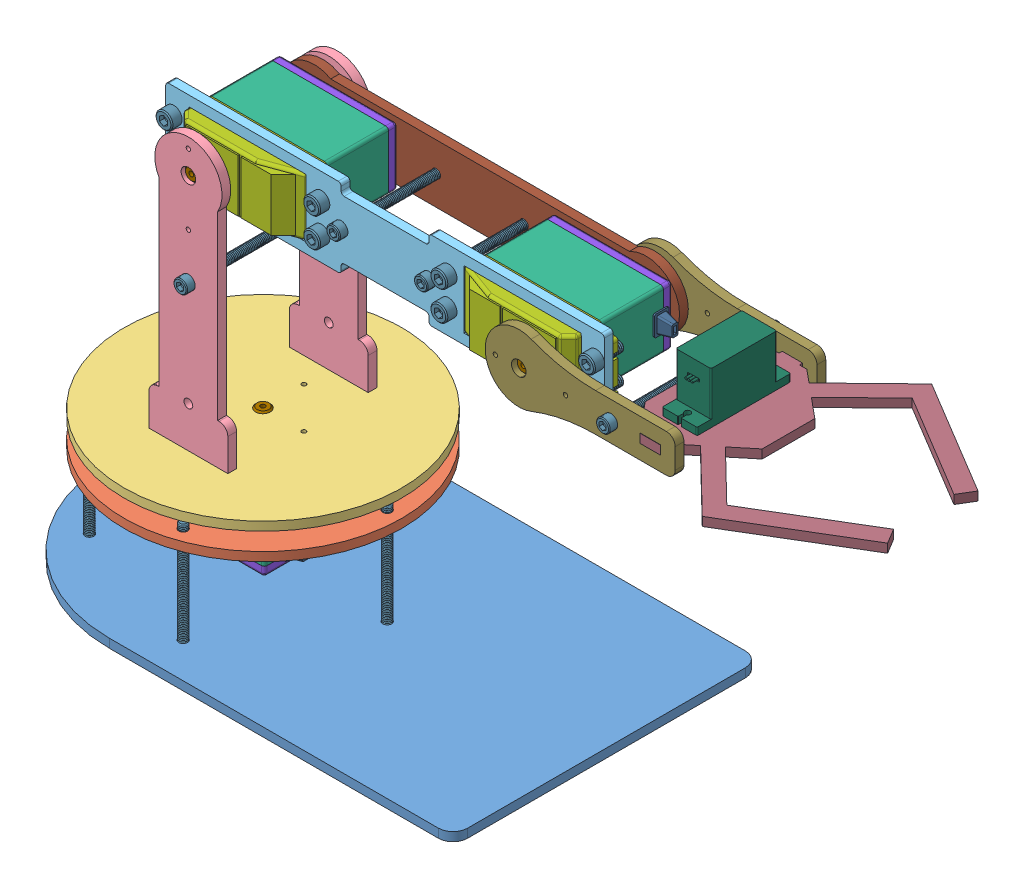
SolidWorks assembly robot_esamble_1_v0, configuration Predeterminado. Lengths in mm.
Overall size (282.35 148.29 105).
56 component instances, 17 part files, 91 mates.
Components (placement in the parent):
- A_pieza_arm_robot_v0-1: A_pieza_arm_robot_v0 [Predeterminado] x (0 0 -1) z (0 1 0) size (105 170 3)
- B_pieza_arm_robot_v0-1: B_pieza_arm_robot_v0 [Predeterminado] at (0 33 0) x (-1 0 0) z (0 1 0) size (95 95 3)
- H_pieza_arm_robot_v0-1: H_pieza_arm_robot_v0 [Predeterminado] at (0 42 0) x (0 0 -1) z (0 1 0) size (95 95 3)
- D_pieza_arm_robot_v0-1: D_pieza_arm_robot_v0 [piexa_motor_leva] at (0 126.5 25.5) x (-1 0 0) z (0 0 -1) size (27 96 3)
- D_pieza_arm_robot_v0-2: D_pieza_arm_robot_v0 [Predeterminado] at (0 126.5 -22.5) x (-1 0 0) z (0 0 -1) size (27 96 3)
- C_pieza_arm_robot_v0-1: C_pieza_arm_robot_v0 [Predeterminado] at (56.75 126.5 12) x (-1 0 0) z (0 0 1) size (150 27 3)
- Servomoteur Futuba S3003-2: Servomoteur Futuba S3003 [Défaut] at (104.1357 166.9 3.2642) x (1 0 0) z (0 -1 0) size (55.5 42.98 32.41)
  - Boitier-1: Boitier [Défaut] at (8.3252 -16.2642 40.4) size (40.4 21 20)
  - Couvercle supérieure-1: Couvercle supérieure [Défaut] at (9.3643 6.7358 40.4) size (55.5 13 20)
  - Couvercle inférieure-1: Couvercle inférieure [Défaut] at (4.9957 -19.3642 40.4) size (40.4 3.1 20)
  - Axe-1: Axe [Défaut] at (9.3643 15.2358 40.4) size (5 16 5)
  - Passe fil-1: Passe fil [Défaut] at (17.8143 -15.2642 40.4) x (0 0 -1) z (1 0 0) size (7 5 7.5)
  - Palonnier-1: Palonnier [Défaut] at (9.3643 21.7358 40.4) x (0.465117 0 -0.885249) z (0 1 0) size (24 24 5) (hidden)
  - Vis CBL Z, M 2.5 - 5-1: Vis CBL Z, M 2.5 - 5 [Défaut] at (9.3643 21.7358 40.4) x (0.991239 0 0.132079) z (0 1 0) size (5 5 6.88) (hidden)
- Servomoteur Futuba S3003-3: Servomoteur Futuba S3003 [Défaut] at (9.3643 86.1 3.2642) x (-1 0 0) z (0 1 0) size (55.5 42.98 32.41)
  - Boitier-1: Boitier [Défaut] at (8.3252 -16.2642 40.4) size (40.4 21 20)
  - Couvercle supérieure-1: Couvercle supérieure [Défaut] at (9.3643 6.7358 40.4) size (55.5 13 20)
  - Couvercle inférieure-1: Couvercle inférieure [Défaut] at (4.9957 -19.3642 40.4) size (40.4 3.1 20)
  - Axe-1: Axe [Défaut] at (9.3643 15.2358 40.4) size (5 16 5)
  - Passe fil-1: Passe fil [Défaut] at (17.8143 -15.2642 40.4) x (0 0 -1) z (1 0 0) size (7 5 7.5)
  - Palonnier-1: Palonnier [Défaut] at (9.3643 21.7358 40.4) x (0.465117 0 -0.885249) z (0 1 0) size (24 24 5) (hidden)
  - Vis CBL Z, M 2.5 - 5-1: Vis CBL Z, M 2.5 - 5 [Défaut] at (9.3643 21.7358 40.4) x (0.991239 0 0.132079) z (0 1 0) size (5 5 6.88) (hidden)
- E_pieza_arm_robot_v0-1: E_pieza_arm_robot_v0 [Predeterminado] at (56.75 126.5 -20.5) x (0 -1 0) z (0 0 1) size (23 136.5 3)
- F_pieza_arm_robot_v0-1: F_pieza_arm_robot_v0 [Predeterminado] at (113.5 126.5 26) x (0 -1 0) z (0 0 -1) size (23 65 3)
- F_pieza_arm_robot_v0-2: F_pieza_arm_robot_v0 [Predeterminado] at (113.5 126.5 -22.5) x (0 -1 0) z (0 0 -1) size (23 65 3)
- G_pieza_arm_robot_v0-1: G_pieza_arm_robot_v0 [Predeterminado] at (158.5 124.95 0.75) x (0 0 1) z (0 1 0) size (78.46 83.35 3)
- socket head cap screw_ai-1: socket head cap screw_ai [HX-SHCS 0.112-48x1.5x1.5-S] at (13.1332 -2.8448 -40.4199) x (0 1 0) z (0 0 1) size (40.94 4.65 4.65)
- socket head cap screw_ai-2: socket head cap screw_ai [HX-SHCS 0.112-48x1.5x1.5-S] at (-34.3832 -2.8448 -24.9809) x (0 1 0) z (0 0 1) size (40.94 4.65 4.65)
- socket head cap screw_ai-3: socket head cap screw_ai [HX-SHCS 0.112-48x1.5x1.5-S] at (-34.3832 -2.8448 24.9809) x (0 1 0) z (0 0 1) size (40.94 4.65 4.65)
- socket head cap screw_ai-4: socket head cap screw_ai [HX-SHCS 0.112-48x1.5x1.5-S] at (13.1332 -2.8448 40.4199) x (0 1 0) z (0 0 1) size (40.94 4.65 4.65)
- socket head cap screw_ai-5: socket head cap screw_ai [HX-SHCS 0.112-48x1.5x1.5-S] at (42.5 -2.8448 0) x (0 1 0) z (0 0 1) size (40.94 4.65 4.65)
- Servomoteur Futuba S3003-4: Servomoteur Futuba S3003 [Défaut] at (-9.3643 24.2642 -40.4) size (55.5 42.98 32.41)
  - Boitier-1: Boitier [Défaut] at (8.3252 -16.2642 40.4) size (40.4 21 20)
  - Couvercle supérieure-1: Couvercle supérieure [Défaut] at (9.3643 6.7358 40.4) size (55.5 13 20)
  - Couvercle inférieure-1: Couvercle inférieure [Défaut] at (4.9957 -19.3642 40.4) size (40.4 3.1 20)
  - Axe-1: Axe [Défaut] at (9.3643 15.2358 40.4) size (5 16 5)
  - Passe fil-1: Passe fil [Défaut] at (17.8143 -15.2642 40.4) x (0 0 -1) z (1 0 0) size (7 5 7.5)
  - Palonnier-1: Palonnier [Défaut] at (9.3643 21.7358 40.4) x (0.465117 0 -0.885249) z (0 1 0) size (24 24 5) (hidden)
  - Vis CBL Z, M 2.5 - 5-1: Vis CBL Z, M 2.5 - 5 [Défaut] at (9.3643 21.7358 40.4) x (0.991239 0 0.132079) z (0 1 0) size (5 5 6.88) (hidden)
- socket head cap screw_ai-6: socket head cap screw_ai [HX-SHCS 0.112-48x2.25x2.25-S] at (0 95 28.3448) x (0 0 -1) z (1 0 0) size (59.99 4.65 4.65)
- socket head cap screw_ai-11: socket head cap screw_ai [HX-SHCS 0.112-48x1.5x1.5-S] at (41.75 126.5 17.8448) x (0 0 -1) z (1 0 0) size (40.94 4.65 4.65)
- socket head cap screw_ai-12: socket head cap screw_ai [HX-SHCS 0.112-48x1.5x1.5-S] at (71.75 126.5 17.8448) x (0 0 -1) z (1 0 0) size (40.94 4.65 4.65)
- socket head cap screw_ai-13: socket head cap screw_ai [HX-SHCS 0.112-48x2.25x2.25-S] at (145 126.5 28.8448) x (0 0 -1) z (1 0 0) size (59.99 4.65 4.65)
- socket head cap screw_ai-14: socket head cap screw_ai [HX-SHCS 0.138-40x0.3125x0.3125-S] at (35 131.5 18.5052) x (0 0 -1) z (1 0 0) size (11.44 5.74 5.74)
- socket head cap screw_ai-15: socket head cap screw_ai [HX-SHCS 0.138-40x0.3125x0.3125-S] at (35 121.5 18.5052) x (0 0 -1) z (1 0 0) size (11.44 5.74 5.74)
- socket head cap screw_ai-16: socket head cap screw_ai [HX-SHCS 0.138-40x0.3125x0.3125-S] at (-15.5 131.5 18.5052) x (0 0 -1) z (1 0 0) size (11.44 5.74 5.74)
- socket head cap screw_ai-17: socket head cap screw_ai [HX-SHCS 0.138-40x0.3125x0.3125-S] at (-15.5 121.5 18.5052) x (0 0 -1) z (1 0 0) size (11.44 5.74 5.74)
- socket head cap screw_ai-18: socket head cap screw_ai [HX-SHCS 0.138-40x0.3125x0.3125-S] at (78.5 131.5 18.5052) x (0 0 -1) z (1 0 0) size (11.44 5.74 5.74)
- socket head cap screw_ai-19: socket head cap screw_ai [HX-SHCS 0.138-40x0.3125x0.3125-S] at (78.5 121.5 18.5052) x (0 0 -1) z (1 0 0) size (11.44 5.74 5.74)
- socket head cap screw_ai-20: socket head cap screw_ai [HX-SHCS 0.138-40x0.3125x0.3125-S] at (129 131.5 18.5052) x (0 0 -1) z (1 0 0) size (11.44 5.74 5.74)
- socket head cap screw_ai-21: socket head cap screw_ai [HX-SHCS 0.138-40x0.3125x0.3125-S] at (129 121.5 18.5052) x (0 0 -1) z (1 0 0) size (11.44 5.74 5.74)
- socket head cap screw_ai-22: socket head cap screw_ai [HX-SHCS 0.138-40x0.3125x0.3125-S] at (15.5 39.5052 5) x (0 -1 0) z (0 0 1) size (11.44 5.74 5.74)
- socket head cap screw_ai-23: socket head cap screw_ai [HX-SHCS 0.138-40x0.3125x0.3125-S] at (15.5 39.5052 -5) x (0 -1 0) z (0 0 1) size (11.44 5.74 5.74)
- socket head cap screw_ai-24: socket head cap screw_ai [HX-SHCS 0.138-40x0.3125x0.3125-S] at (-35 39.5052 5) x (0 -1 0) z (0 0 1) size (11.44 5.74 5.74)
- socket head cap screw_ai-25: socket head cap screw_ai [HX-SHCS 0.138-40x0.3125x0.3125-S] at (-35 39.5052 -5) x (0 -1 0) z (0 0 1) size (11.44 5.74 5.74)
- Towerpro Micro Servo 9g-1: Towerpro Micro Servo 9g [Varsayılan] at (159.5 145.45 1) x (1 0 0) z (0 0 -1) size (12 30 32)
Mates (geometry in assembly coordinates):
- Coincidente1: coincident anti-aligned: plane of A_pieza_arm_robot_v0-1 through (0 0 0) normal (0 -1 0)
- Coincidente2: coincident anti-aligned: plane of A_pieza_arm_robot_v0-1 through (0 0 0) normal (0 0 -1)
- Coincidente3: coincident anti-aligned: plane of A_pieza_arm_robot_v0-1 through (0 0 0) normal (-1 0 0)
- Distancia1: distance = 30 mm anti-aligned: plane of B_pieza_arm_robot_v0-1 through (0 33 0) normal (0 -1 0); plane of A_pieza_arm_robot_v0-1 through (0 3 0) normal (0 1 0)
- Concéntrica1: concentric aligned: cylinder of A_pieza_arm_robot_v0-1 through (42.5 0 0) axis (0 1 0) radius 1.5; cylinder of B_pieza_arm_robot_v0-1 through (42.5 33 0) axis (0 1 0) radius 1.5
- Concéntrica2: concentric aligned: cylinder of A_pieza_arm_robot_v0-1 through (-34.3832 0 24.9809) axis (0 1 0) radius 1.5; cylinder of B_pieza_arm_robot_v0-1 through (-34.3832 33 24.9809) axis (0 1 0) radius 1.5
- Concéntrica3: concentric aligned: cylinder of B_pieza_arm_robot_v0-1 through (0 36 0) axis (0 -1 0) radius 47.5; cylinder of H_pieza_arm_robot_v0-1 through (0 45 0) axis (0 -1 0) radius 47.5
- Distancia2: distance = 6 mm anti-aligned: plane of B_pieza_arm_robot_v0-1 through (0 36 0) normal (0 1 0); plane of H_pieza_arm_robot_v0-1 through (0 42 0) normal (0 -1 0)
- Coincidente6: coincident anti-aligned: plane of H_pieza_arm_robot_v0-1 through (2.5 42 25.5) normal (0 0 -1); plane of D_pieza_arm_robot_v0-1 through (0 126.5 25.5) normal (0 0 1)
- Coincidente7: coincident anti-aligned: plane of H_pieza_arm_robot_v0-1 through (10.5 42 22.5) normal (-1 0 0); plane of D_pieza_arm_robot_v0-1 through (10.5 45 25.5) normal (1 0 0)
- Coincidente8: coincident anti-aligned: plane of H_pieza_arm_robot_v0-1 through (0 45 0) normal (0 1 0); plane of D_pieza_arm_robot_v0-1 through (0 45 22.5) normal (0 -1 0)
- Coincidente9: coincident anti-aligned: plane of H_pieza_arm_robot_v0-1 through (-10.5 42 -22.5) normal (1 0 0); plane of D_pieza_arm_robot_v0-2 through (-10.5 45 -22.5) normal (-1 0 0)
- Coincidente10: coincident anti-aligned: plane of H_pieza_arm_robot_v0-1 through (-10.5 42 -25.5) normal (0 0 1); plane of D_pieza_arm_robot_v0-2 through (0 126.5 -25.5) normal (0 0 -1)
- Coincidente12: coincident anti-aligned: plane of H_pieza_arm_robot_v0-1 through (0 45 0) normal (0 1 0); plane of D_pieza_arm_robot_v0-2 through (0 45 -25.5) normal (0 -1 0)
- Coincidente13: coincident anti-aligned: plane of C_pieza_arm_robot_v0-1 through (56.75 126.5 12) normal (0 0 -1); plane of Servomoteur Futuba S3003-2/Couvercle supérieure-1 through (78.5 131.5 12) normal (0 0 1)
- Concéntrica6: concentric anti-aligned: cylinder of C_pieza_arm_robot_v0-1 through (129 121.5 12) axis (0 0 1) radius 2; cylinder of Servomoteur Futuba S3003-2/Couvercle supérieure-1 through (129 121.5 12) axis (0 0 -1) radius 2
- Concéntrica7: concentric anti-aligned: cylinder of C_pieza_arm_robot_v0-1 through (129 131.5 12) axis (0 0 1) radius 2; cylinder of Servomoteur Futuba S3003-2/Couvercle supérieure-1 through (129 131.5 12) axis (0 0 -1) radius 2
- Coincidente14: coincident anti-aligned: plane of C_pieza_arm_robot_v0-1 through (56.75 126.5 12) normal (0 0 -1); plane of Servomoteur Futuba S3003-3/Couvercle supérieure-1 through (35 121.5 12) normal (0 0 1)
- Concéntrica8: concentric anti-aligned: cylinder of C_pieza_arm_robot_v0-1 through (-15.5 121.5 12) axis (0 0 1) radius 2; cylinder of Servomoteur Futuba S3003-3/Couvercle supérieure-1 through (-15.5 121.5 12) axis (0 0 -1) radius 2
- Concéntrica9: concentric anti-aligned: cylinder of C_pieza_arm_robot_v0-1 through (-15.5 131.5 12) axis (0 0 1) radius 2; cylinder of Servomoteur Futuba S3003-3/Couvercle supérieure-1 through (-15.5 131.5 12) axis (0 0 -1) radius 2
- Concéntrica10: concentric anti-aligned: cylinder of D_pieza_arm_robot_v0-1 through (0 126.5 25.5) axis (0 0 -1) radius 2.5; cylinder of Servomoteur Futuba S3003-3/Axe-1 through (0 126.5 8.5) axis (0 0 1) radius 2.5
- Distancia3: distance = 1 mm aligned: plane of D_pieza_arm_robot_v0-1 through (0 126.5 25.5) normal (0 0 1); plane of Servomoteur Futuba S3003-3/Axe-1 through (0 126.5 24.5) normal (0 0 1)
- Concéntrica11: concentric anti-aligned: cylinder of D_pieza_arm_robot_v0-2 through (0 126.5 -22.5) axis (0 0 -1) radius 2.5; cylinder of E_pieza_arm_robot_v0-1 through (0 126.5 -20.5) axis (0 0 1) radius 1.5
- Distancia4: distance = 2 mm anti-aligned: plane of E_pieza_arm_robot_v0-1 through (56.75 126.5 -20.5) normal (0 0 -1); plane of D_pieza_arm_robot_v0-2 through (0 126.5 -22.5) normal (0 0 1)
- Paralelo3: parallel aligned: plane of C_pieza_arm_robot_v0-1 through (41.75 116.5 15) normal (0 -1 0); plane of E_pieza_arm_robot_v0-1 through (56.75 116.5 -17.5) normal (0 -1 0)
- Concéntrica16: concentric anti-aligned: cylinder of Servomoteur Futuba S3003-2/Axe-1 through (113.5 126.5 8.5) axis (0 0 1) radius 2.5; cylinder of F_pieza_arm_robot_v0-1 through (113.5 126.5 26) axis (0 0 -1) radius 2.5
- Distancia6: distance = 8 mm anti-aligned: plane of F_pieza_arm_robot_v0-1 through (113.5 126.5 23) normal (0 0 -1); plane of C_pieza_arm_robot_v0-1 through (56.75 126.5 15) normal (0 0 1)
- Concéntrica17: concentric anti-aligned: cylinder of E_pieza_arm_robot_v0-1 through (113.5 126.5 -20.5) axis (0 0 1) radius 1.5; cylinder of F_pieza_arm_robot_v0-2 through (113.5 126.5 -22.5) axis (0 0 -1) radius 2.5
- Distancia7: distance = 2 mm anti-aligned: plane of F_pieza_arm_robot_v0-2 through (113.5 126.5 -22.5) normal (0 0 1); plane of E_pieza_arm_robot_v0-1 through (56.75 126.5 -20.5) normal (0 0 -1)
- Coincidente21: coincident anti-aligned: plane of F_pieza_arm_robot_v0-1 through (155 124.95 26) normal (0 1 0); plane of G_pieza_arm_robot_v0-1 through (158.5 124.95 0.75) normal (0 -1 0)
- Coincidente23: coincident aligned: plane of F_pieza_arm_robot_v0-1 through (113.5 126.5 26) normal (0 0 1); plane of G_pieza_arm_robot_v0-1 through (158.5 127.95 26) normal (0 0 1)
- Coincidente24: coincident anti-aligned: plane of F_pieza_arm_robot_v0-1 through (162 124.95 26) normal (-1 0 0); plane of G_pieza_arm_robot_v0-1 through (162 127.95 0.75) normal (1 0 0)
- Coincidente25: coincident anti-aligned: plane of F_pieza_arm_robot_v0-2 through (155 124.95 -22.5) normal (0 1 0); plane of G_pieza_arm_robot_v0-1 through (158.5 124.95 0.75) normal (0 -1 0)
- Concéntrica21: concentric anti-aligned: cylinder of A_pieza_arm_robot_v0-1 through (13.1332 0 -40.4199) axis (0 1 0) radius 1.5; cylinder of socket head cap screw_ai-1 through (13.1332 -34.5948 -40.4199) axis (0 -1 0) radius 2.3241
- Coincidente29: coincident anti-aligned: plane of A_pieza_arm_robot_v0-1 through (0 0 0) normal (0 -1 0); plane of socket head cap screw_ai-1 through (10.8091 0 -40.4199) normal (0 1 0)
- Concéntrica22: concentric anti-aligned: cylinder of A_pieza_arm_robot_v0-1 through (-34.3832 0 -24.9809) axis (0 1 0) radius 1.5; cylinder of socket head cap screw_ai-2 through (-34.3832 -34.5948 -24.9809) axis (0 -1 0) radius 2.3241
- Coincidente30: coincident anti-aligned: plane of A_pieza_arm_robot_v0-1 through (0 0 0) normal (0 -1 0); plane of socket head cap screw_ai-2 through (-36.7073 0 -24.9809) normal (0 1 0)
- Concéntrica23: concentric anti-aligned: cylinder of A_pieza_arm_robot_v0-1 through (-34.3832 0 24.9809) axis (0 1 0) radius 1.5; cylinder of socket head cap screw_ai-3 through (-34.3832 -34.5948 24.9809) axis (0 -1 0) radius 2.3241
- Coincidente31: coincident anti-aligned: plane of A_pieza_arm_robot_v0-1 through (0 0 0) normal (0 -1 0); plane of socket head cap screw_ai-3 through (-36.7073 0 24.9809) normal (0 1 0)
- Concéntrica24: concentric anti-aligned: cylinder of A_pieza_arm_robot_v0-1 through (13.1332 0 40.4199) axis (0 1 0) radius 1.5; cylinder of socket head cap screw_ai-4 through (13.1332 -34.5948 40.4199) axis (0 -1 0) radius 2.3241
- Coincidente32: coincident anti-aligned: plane of A_pieza_arm_robot_v0-1 through (0 0 0) normal (0 -1 0); plane of socket head cap screw_ai-4 through (10.8091 0 40.4199) normal (0 1 0)
- Concéntrica25: concentric anti-aligned: cylinder of A_pieza_arm_robot_v0-1 through (42.5 0 0) axis (0 1 0) radius 1.5; cylinder of socket head cap screw_ai-5 through (42.5 -34.5948 0) axis (0 -1 0) radius 2.3241
- Coincidente33: coincident anti-aligned: plane of A_pieza_arm_robot_v0-1 through (0 0 0) normal (0 -1 0); plane of socket head cap screw_ai-5 through (40.1759 0 0) normal (0 1 0)
- Coincidente34: coincident anti-aligned: plane of B_pieza_arm_robot_v0-1 through (0 33 0) normal (0 -1 0); plane of Servomoteur Futuba S3003-4/Couvercle supérieure-1 through (-35 33 -5) normal (0 1 0)
- Concéntrica28: concentric anti-aligned: cylinder of B_pieza_arm_robot_v0-1 through (-35 33 5) axis (0 1 0) radius 2; cylinder of Servomoteur Futuba S3003-4/Couvercle supérieure-1 through (-35 33 5) axis (0 -1 0) radius 2
- Concéntrica29: concentric anti-aligned: cylinder of B_pieza_arm_robot_v0-1 through (-35 33 -5) axis (0 1 0) radius 2; cylinder of Servomoteur Futuba S3003-4/Couvercle supérieure-1 through (-35 33 -5) axis (0 -1 0) radius 2
- Concéntrica30: concentric anti-aligned: cylinder of D_pieza_arm_robot_v0-1 through (0 95 25.5) axis (0 0 -1) radius 1.5; cylinder of socket head cap screw_ai-6 through (0 95 60.0948) axis (0 0 1) radius 2.3241
- Coincidente35: coincident anti-aligned: plane of D_pieza_arm_robot_v0-1 through (0 126.5 25.5) normal (0 0 1); plane of socket head cap screw_ai-6 through (0 97.3241 25.5) normal (0 0 -1)
- Concéntrica31: concentric aligned: cylinder of C_pieza_arm_robot_v0-1 through (41.75 126.5 12) axis (0 0 1) radius 1.5; cylinder of socket head cap screw_ai-7 through (64.7787 129.0283 0.1988) axis (0.763622 0 0.645663) radius 2.3241
- Coincidente36: coincident anti-aligned: plane of C_pieza_arm_robot_v0-1 through (56.75 126.5 15) normal (0 0 1); plane of socket head cap screw_ai-7 through (38.3613 131.3524 -22.1378) normal (-0.763622 0 -0.645663)
- Concéntrica32: concentric aligned: cylinder of C_pieza_arm_robot_v0-1 through (71.75 126.5 12) axis (0 0 1) radius 1.5; cylinder of socket head cap screw_ai-9 through (84.113 130.8451 -22.6678) axis (0.763622 0 0.645663) radius 2.3241
- Coincidente38: coincident anti-aligned: plane of C_pieza_arm_robot_v0-1 through (56.75 126.5 15) normal (0 0 1); plane of socket head cap screw_ai-9 through (57.6956 133.1692 -45.0044) normal (-0.763622 0 -0.645663)
- Concéntrica33: concentric anti-aligned: cylinder of F_pieza_arm_robot_v0-1 through (145 126.5 26) axis (0 0 -1) radius 1.5; cylinder of socket head cap screw_ai-10 through (138.4716 144.3994 -69.9206) axis (0.763622 0 0.645663) radius 2.3241
- Coincidente39: coincident anti-aligned: plane of F_pieza_arm_robot_v0-1 through (113.5 126.5 26) normal (0 0 1); plane of socket head cap screw_ai-10 through (112.0542 146.7235 -92.2572) normal (-0.763622 0 -0.645663)
- Concéntrica34: concentric aligned: cylinder of C_pieza_arm_robot_v0-1 through (41.75 126.5 12) axis (0 0 1) radius 1.5; cylinder of socket head cap screw_ai-11 through (41.75 126.5 49.5948) axis (0 0 1) radius 2.3241
- Coincidente40: coincident anti-aligned: plane of C_pieza_arm_robot_v0-1 through (56.75 126.5 15) normal (0 0 1); plane of socket head cap screw_ai-11 through (41.75 128.8241 15) normal (0 0 -1)
- Concéntrica35: concentric aligned: cylinder of C_pieza_arm_robot_v0-1 through (71.75 126.5 12) axis (0 0 1) radius 1.5; cylinder of socket head cap screw_ai-12 through (71.75 126.5 49.5948) axis (0 0 1) radius 2.3241
- Coincidente41: coincident anti-aligned: plane of C_pieza_arm_robot_v0-1 through (56.75 126.5 15) normal (0 0 1); plane of socket head cap screw_ai-12 through (71.75 128.8241 15) normal (0 0 -1)
- Concéntrica36: concentric anti-aligned: cylinder of F_pieza_arm_robot_v0-1 through (145 126.5 26) axis (0 0 -1) radius 1.5; cylinder of socket head cap screw_ai-13 through (145 126.5 60.5948) axis (0 0 1) radius 2.3241
- Coincidente42: coincident anti-aligned: plane of F_pieza_arm_robot_v0-1 through (113.5 126.5 26) normal (0 0 1); plane of socket head cap screw_ai-13 through (145 128.8241 26) normal (0 0 -1)
- Concéntrica37: concentric aligned: cylinder of C_pieza_arm_robot_v0-1 through (35 131.5 12) axis (0 0 1) radius 2; cylinder of socket head cap screw_ai-14 through (35 131.5 50.2552) axis (0 0 1) radius 2.8702
- Coincidente43: coincident anti-aligned: plane of C_pieza_arm_robot_v0-1 through (56.75 126.5 15) normal (0 0 1); plane of socket head cap screw_ai-14 through (35 134.3702 15) normal (0 0 -1)
- Concéntrica38: concentric aligned: cylinder of C_pieza_arm_robot_v0-1 through (35 121.5 12) axis (0 0 1) radius 2; cylinder of socket head cap screw_ai-15 through (35 121.5 50.2552) axis (0 0 1) radius 2.8702
- Coincidente44: coincident anti-aligned: plane of C_pieza_arm_robot_v0-1 through (56.75 126.5 15) normal (0 0 1); plane of socket head cap screw_ai-15 through (35 124.3702 15) normal (0 0 -1)
- Concéntrica39: concentric aligned: cylinder of C_pieza_arm_robot_v0-1 through (-15.5 131.5 12) axis (0 0 1) radius 2; cylinder of socket head cap screw_ai-16 through (-15.5 131.5 50.2552) axis (0 0 1) radius 2.8702
- Coincidente45: coincident anti-aligned: plane of C_pieza_arm_robot_v0-1 through (56.75 126.5 15) normal (0 0 1); plane of socket head cap screw_ai-16 through (-15.5 134.3702 15) normal (0 0 -1)
- Concéntrica40: concentric aligned: cylinder of C_pieza_arm_robot_v0-1 through (-15.5 121.5 12) axis (0 0 1) radius 2; cylinder of socket head cap screw_ai-17 through (-15.5 121.5 50.2552) axis (0 0 1) radius 2.8702
- Coincidente46: coincident anti-aligned: plane of C_pieza_arm_robot_v0-1 through (56.75 126.5 15) normal (0 0 1); plane of socket head cap screw_ai-17 through (-15.5 124.3702 15) normal (0 0 -1)
- Concéntrica41: concentric aligned: cylinder of C_pieza_arm_robot_v0-1 through (78.5 131.5 12) axis (0 0 1) radius 2; cylinder of socket head cap screw_ai-18 through (78.5 131.5 50.2552) axis (0 0 1) radius 2.8702
- Coincidente47: coincident anti-aligned: plane of C_pieza_arm_robot_v0-1 through (56.75 126.5 15) normal (0 0 1); plane of socket head cap screw_ai-18 through (78.5 134.3702 15) normal (0 0 -1)
- Concéntrica42: concentric aligned: cylinder of C_pieza_arm_robot_v0-1 through (78.5 121.5 12) axis (0 0 1) radius 2; cylinder of socket head cap screw_ai-19 through (78.5 121.5 50.2552) axis (0 0 1) radius 2.8702
- Coincidente48: coincident anti-aligned: plane of C_pieza_arm_robot_v0-1 through (56.75 126.5 15) normal (0 0 1); plane of socket head cap screw_ai-19 through (78.5 124.3702 15) normal (0 0 -1)
- Concéntrica43: concentric aligned: cylinder of C_pieza_arm_robot_v0-1 through (129 131.5 12) axis (0 0 1) radius 2; cylinder of socket head cap screw_ai-20 through (129 131.5 50.2552) axis (0 0 1) radius 2.8702
- Coincidente49: coincident anti-aligned: plane of C_pieza_arm_robot_v0-1 through (56.75 126.5 15) normal (0 0 1); plane of socket head cap screw_ai-20 through (129 134.3702 15) normal (0 0 -1)
- Concéntrica44: concentric aligned: cylinder of C_pieza_arm_robot_v0-1 through (129 121.5 12) axis (0 0 1) radius 2; cylinder of socket head cap screw_ai-21 through (129 121.5 50.2552) axis (0 0 1) radius 2.8702
- Coincidente50: coincident anti-aligned: plane of C_pieza_arm_robot_v0-1 through (56.75 126.5 15) normal (0 0 1); plane of socket head cap screw_ai-21 through (129 124.3702 15) normal (0 0 -1)
- Concéntrica45: concentric aligned: cylinder of B_pieza_arm_robot_v0-1 through (15.5 33 5) axis (0 1 0) radius 2; cylinder of socket head cap screw_ai-22 through (15.5 71.2552 5) axis (0 1 0) radius 2.8702
- Coincidente51: coincident anti-aligned: plane of B_pieza_arm_robot_v0-1 through (0 36 0) normal (0 1 0); plane of socket head cap screw_ai-22 through (18.3702 36 5) normal (0 -1 0)
- Concéntrica46: concentric aligned: cylinder of B_pieza_arm_robot_v0-1 through (15.5 33 -5) axis (0 1 0) radius 2; cylinder of socket head cap screw_ai-23 through (15.5 71.2552 -5) axis (0 1 0) radius 2.8702
- Coincidente52: coincident anti-aligned: plane of B_pieza_arm_robot_v0-1 through (0 36 0) normal (0 1 0); plane of socket head cap screw_ai-23 through (18.3702 36 -5) normal (0 -1 0)
- Concéntrica47: concentric aligned: cylinder of B_pieza_arm_robot_v0-1 through (-35 33 5) axis (0 1 0) radius 2; cylinder of socket head cap screw_ai-24 through (-35 71.2552 5) axis (0 1 0) radius 2.8702
- Coincidente53: coincident anti-aligned: plane of B_pieza_arm_robot_v0-1 through (0 36 0) normal (0 1 0); plane of socket head cap screw_ai-24 through (-32.1298 36 5) normal (0 -1 0)
- Concéntrica48: concentric aligned: cylinder of B_pieza_arm_robot_v0-1 through (-35 33 -5) axis (0 1 0) radius 2; cylinder of socket head cap screw_ai-25 through (-35 71.2552 -5) axis (0 1 0) radius 2.8702
- Coincidente54: coincident anti-aligned: plane of B_pieza_arm_robot_v0-1 through (0 36 0) normal (0 1 0); plane of socket head cap screw_ai-25 through (-32.1298 36 -5) normal (0 -1 0)
- Coincidente55: coincident anti-aligned: plane of G_pieza_arm_robot_v0-1 through (158.5 127.95 0.75) normal (0 1 0); plane of Towerpro Micro Servo 9g-1 through (165 127.95 -14.5) normal (0 -1 0)
- Distancia8: distance = 15 mm aligned: plane of Towerpro Micro Servo 9g-1 through (165.5 144.45 11.75) normal (1 0 0); plane of G_pieza_arm_robot_v0-1 through (180.5 127.95 0.75) normal (1 0 0)
- Distancia9: distance = 6 mm anti-aligned: plane of Towerpro Micro Servo 9g-1 through (160.2 127.95 17) normal (0 0 1); plane of F_pieza_arm_robot_v0-1 through (113.5 126.5 23) normal (0 0 -1)
- Paralelo6: parallel anti-aligned: plane of A_pieza_arm_robot_v0-1 through (0 3 0) normal (0 1 0); plane of E_pieza_arm_robot_v0-1 through (56.75 116.5 -17.5) normal (0 -1 0)
- Paralelo7: parallel aligned: plane of A_pieza_arm_robot_v0-1 through (0 3 -52.5) normal (0 0 -1); plane of D_pieza_arm_robot_v0-2 through (0 126.5 -25.5) normal (0 0 -1)
- Paralelo8: parallel anti-aligned: plane of A_pieza_arm_robot_v0-1 through (0 3 0) normal (0 1 0); plane of C_pieza_arm_robot_v0-1 through (41.75 116.5 15) normal (0 -1 0)
- Paralelo9: parallel aligned: plane of C_pieza_arm_robot_v0-1 through (41.75 136.5 15) normal (0 1 0); plane of F_pieza_arm_robot_v0-1 through (113.5 133 23) normal (0 1 0)
